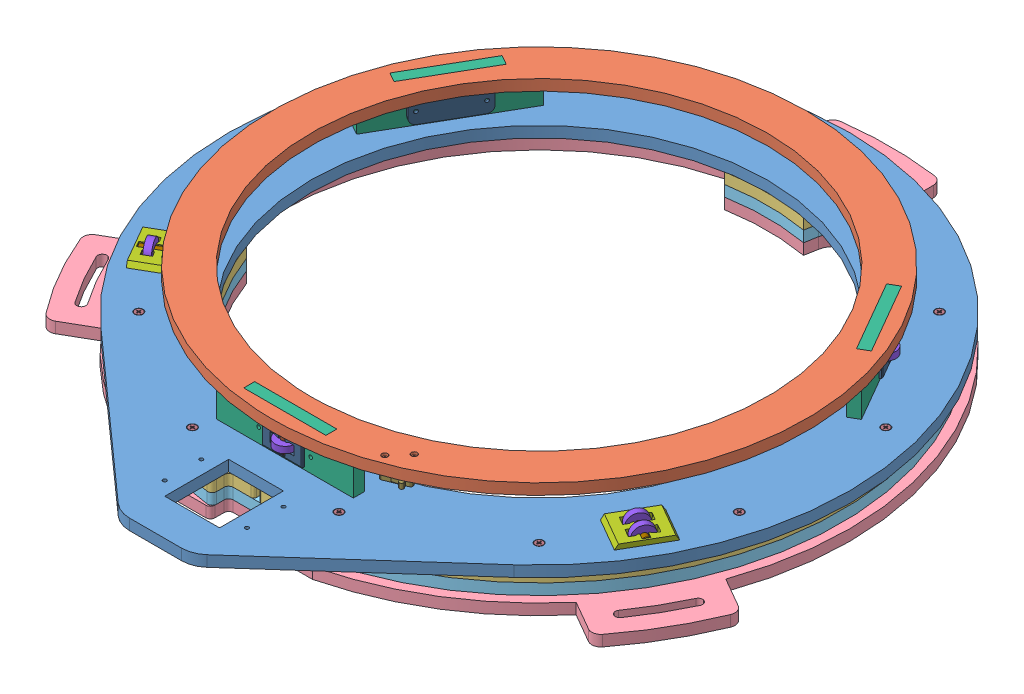
SolidWorks assembly Base Assembly - Plywood Parts, configuration Default. Lengths in mm.
Overall size (713.72 92.45 805).
48 component instances, 13 part files, 40 mates.
Components (placement in the parent):
- Base - Bottom Ring-1: Base - Bottom Ring [Default] at origin size (680 12 760)
- Base - Top Ring-1: Base - Top Ring [Default] at (0 114.9148 0) size (585 12 585)
- Base - Cable carrier ring-1: Base - Cable carrier ring [Default] at (0 -447.8958 0) x (1 0 0) z (0 -1 0) size (660 658.11 12)
- Base - Base Ring-1: Base - Base Ring [Default] at (0 34.4648 0) size (713.72 12 715)
- Base - Cable carrier ring lower-3: Base - Cable carrier ring lower [Default] at (0 58.4648 0) x (1 0 0) z (0 -1 0) size (660 658.11 12)
- Base - Uprights-4: Base - Uprights [Default] at (7.2575 0 46.252) size (150 56.45 12)
- Wide Roller Assem-4: Wide Roller Assem [Default] at (-232.883 45.169 131.3254) x (0.5 0 0.866025) z (-0.866025 0 0.5) size (52.45 32.7 42)
  - Wide Roller-1: Wide Roller [Default] at (2.4854 34.9145 44.1547) size (52.45 25.2 42)
  - 608 Bearing-1: 608 Bearing [Default] at (2.4854 38.9958 40.6547) x (1 0 0) z (0 -1 0) size (22 7 22)
  - 608 Bearing-2: 608 Bearing [Default] at (2.4854 38.9958 23.6547) x (1 0 0) z (0 -1 0) size (22 7 22)
  - Long 8mm Shaft-1: Long 8mm Shaft [Default] at (2.4854 38.9958 16.6547) size (8 8 38)
- Roller Assem-4: Roller Assem [Default] at (-3.9974 147.3095 228.5536) x (1 0 0) z (0 -1 0) size (70 29.66 25)
  - Roller-1: Roller [Default] at (3.7724 45.3652 49.3947) size (70 18.5 25)
  - 608 Bearing-1: 608 Bearing [Default] at (3.7724 49.4464 52.8947) x (0.903242 0.429132 0) z (-0.429132 0.903242 0) size (22 7 22)
  - Short 8mm Shaft-1: Short 8mm Shaft [Default] at (3.7724 49.4464 38.8947) size (8 8 21)
- Base - Uprights-5: Base - Uprights [Default] at (36.4267 0 -29.4112) x (-0.5 0 -0.866025) z (0.866025 0 -0.5) size (150 56.45 12)
- Base - Uprights-6: Base - Uprights [Default] at (-43.6841 0 -16.8408) x (-0.5 0 0.866025) z (-0.866025 0 -0.5) size (150 56.45 12)
- Roller Assem-5: Roller Assem [Default] at (199.9319 147.3095 -110.8149) x (-0.5 0 -0.866025) z (0 -1 0) size (70 29.66 25)
  - Roller-1: Roller [Default] at (3.7724 45.3652 49.3947) size (70 18.5 25)
  - 608 Bearing-1: 608 Bearing [Default] at (3.7724 49.4464 52.8947) x (0.903242 0.429132 0) z (-0.429132 0.903242 0) size (22 7 22)
  - Short 8mm Shaft-1: Short 8mm Shaft [Default] at (3.7724 49.4464 38.8947) size (8 8 21)
- Roller Assem-6: Roller Assem [Default] at (-195.9345 147.3095 -117.7386) x (-0.5 0 0.866025) z (0 -1 0) size (70 29.66 25)
  - Roller-1: Roller [Default] at (3.7724 45.3652 49.3947) size (70 18.5 25)
  - 608 Bearing-1: 608 Bearing [Default] at (3.7724 49.4464 52.8947) x (0.903242 0.429132 0) z (-0.429132 0.903242 0) size (22 7 22)
  - Short 8mm Shaft-1: Short 8mm Shaft [Default] at (3.7724 49.4464 38.8947) size (8 8 21)
- Wide Roller Assem-5: Wide Roller Assem [Default] at (230.1726 45.169 136.0199) x (0.5 0 -0.866025) z (0.866025 0 0.5) size (52.45 32.7 42)
  - Wide Roller-1: Wide Roller [Default] at (2.4854 34.9145 44.1547) size (52.45 25.2 42)
  - 608 Bearing-1: 608 Bearing [Default] at (2.4854 38.9958 40.6547) x (1 0 0) z (0 -1 0) size (22 7 22)
  - 608 Bearing-2: 608 Bearing [Default] at (2.4854 38.9958 23.6547) x (1 0 0) z (0 -1 0) size (22 7 22)
  - Long 8mm Shaft-1: Long 8mm Shaft [Default] at (2.4854 38.9958 16.6547) size (8 8 38)
- Wide Roller Assem-6: Wide Roller Assem [Default] at (2.7104 45.169 -267.3453) x (-1 0 0) z (0 0 -1) size (52.45 32.7 42)
  - Wide Roller-1: Wide Roller [Default] at (2.4854 34.9145 44.1547) size (52.45 25.2 42)
  - 608 Bearing-1: 608 Bearing [Default] at (2.4854 38.9958 40.6547) x (1 0 0) z (0 -1 0) size (22 7 22)
  - 608 Bearing-2: 608 Bearing [Default] at (2.4854 38.9958 23.6547) x (1 0 0) z (0 -1 0) size (22 7 22)
  - Long 8mm Shaft-1: Long 8mm Shaft [Default] at (2.4854 38.9958 16.6547) size (8 8 38)
- Limit Switch-1: Limit Switch [Default] at (113.6125 109.9148 243.8282) x (-0.927184 0 0.374607) z (0 1 0) size (37 27.92 10)
- flat head screw_am-14: flat head screw_am [B18.6.7M - M4 x 0.7 x 40 Type I Cross Recessed FHMS --40N] at (80.2339 82.4648 -299.437) x (0 -1 0) z (0 0 1) size (40 8.4 8.4)
- flat head screw_am-15: flat head screw_am [B18.6.7M - M4 x 0.7 x 40 Type I Cross Recessed FHMS --40N] at (219.2031 82.4648 -219.2031) x (0 -1 0) z (0 0 1) size (40 8.4 8.4)
- flat head screw_am-16: flat head screw_am [B18.6.7M - M4 x 0.7 x 40 Type I Cross Recessed FHMS --40N] at (299.437 82.4648 -80.2339) x (0 -1 0) z (0 0 1) size (40 8.4 8.4)
- flat head screw_am-17: flat head screw_am [B18.6.7M - M4 x 0.7 x 40 Type I Cross Recessed FHMS --40N] at (299.437 82.4648 80.2339) x (0 -1 0) z (0 0 1) size (40 8.4 8.4)
- flat head screw_am-18: flat head screw_am [B18.6.7M - M4 x 0.7 x 40 Type I Cross Recessed FHMS --40N] at (219.2031 82.4648 219.2031) x (0 -1 0) z (0 0 1) size (40 8.4 8.4)
- flat head screw_am-19: flat head screw_am [B18.6.7M - M4 x 0.7 x 40 Type I Cross Recessed FHMS --40N] at (80.2339 82.4648 299.437) x (0 -1 0) z (0 0 1) size (40 8.4 8.4)
- flat head screw_am-20: flat head screw_am [B18.6.7M - M4 x 0.7 x 40 Type I Cross Recessed FHMS --40N] at (-80.2339 82.4648 299.437) x (0 -1 0) z (0 0 1) size (40 8.4 8.4)
- flat head screw_am-21: flat head screw_am [B18.6.7M - M4 x 0.7 x 40 Type I Cross Recessed FHMS --40N] at (-219.2031 82.4648 219.2031) x (0 -1 0) z (0 0 1) size (40 8.4 8.4)
- flat head screw_am-22: flat head screw_am [B18.6.7M - M4 x 0.7 x 40 Type I Cross Recessed FHMS --40N] at (-299.437 82.4648 80.2339) x (0 -1 0) z (0 0 1) size (40 8.4 8.4)
- flat head screw_am-23: flat head screw_am [B18.6.7M - M4 x 0.7 x 40 Type I Cross Recessed FHMS --40N] at (-299.437 82.4648 -80.2339) x (0 -1 0) z (0 0 1) size (40 8.4 8.4)
- flat head screw_am-24: flat head screw_am [B18.6.7M - M4 x 0.7 x 40 Type I Cross Recessed FHMS --40N] at (-219.2031 82.4648 -219.2031) x (0 -1 0) z (0 0 1) size (40 8.4 8.4)
- flat head screw_am-25: flat head screw_am [B18.6.7M - M4 x 0.7 x 40 Type I Cross Recessed FHMS --40N] at (-80.2339 82.4648 -299.437) x (0 -1 0) z (0 0 1) size (40 8.4 8.4)
Mates (geometry in assembly coordinates):
- Concentric2: concentric anti-aligned: circle of Base - Bottom Ring-1; circle of Base - Cable carrier ring lower-3
- Coincident58: coincident anti-aligned: plane of Base - Cable carrier ring-1 through (0 58.4648 0) normal (0 -1 0); plane of Base - Cable carrier ring lower-3 through (0 58.4648 0) normal (0 1 0)
- Coincident59: coincident aligned: line of Base - Cable carrier ring-1 through (234.9232 70.4648 85.505) axis (0 -1 0); line of Base - Cable carrier ring lower-3 through (234.9232 58.4648 85.505) axis (0 -1 0)
- Coincident60: coincident anti-aligned: plane of Base - Base Ring-1 through (0 46.4648 0) normal (0 1 0); plane of Base - Cable carrier ring lower-3 through (0 46.4648 0) normal (0 -1 0)
- Coincident62: coincident anti-aligned: line of Base - Base Ring-1 through (43.412 34.4648 -246.2019) axis (0 1 0); line of Base - Cable carrier ring lower-3 through (43.412 58.4648 -246.2019) axis (0 -1 0)
- Concentric4: concentric aligned: cylinder of Base - Cable carrier ring-1 through (0 58.4648 0) axis (0 1 0) radius 330; cylinder of Base - Cable carrier ring lower-3 through (0 46.4648 0) axis (0 1 0) radius 330
- Coincident63: coincident anti-aligned: plane of Base - Cable carrier ring-1 through (0 58.4648 0) normal (0 -1 0); plane of Base - Cable carrier ring lower-3 through (0 58.4648 0) normal (0 1 0)
- Coincident64: coincident anti-aligned: plane of Base - Cable carrier ring-1 through (0 58.4648 0) normal (0 -1 0); plane of Base - Cable carrier ring lower-3 through (0 58.4648 0) normal (0 1 0)
- Coincident65: coincident anti-aligned: plane of Base - Bottom Ring-1 through (0 70.4648 0) normal (0 -1 0); plane of Base - Cable carrier ring-1 through (0 70.4648 0) normal (0 1 0)
- Concentric5: concentric aligned: circle of Base - Bottom Ring-1; circle of Base - Top Ring-1
- Concentric6: concentric anti-aligned: cylinder of Base - Bottom Ring-1 through (0 70.4648 0) axis (0 1 0) radius 340; cylinder of Base - Base Ring-1 through (0 46.4648 0) axis (0 -1 0) radius 340
- Parallel1: parallel aligned: plane of Base - Bottom Ring-1 through (-30 70.4648 310) normal (0 0 1); plane of Base - Base Ring-1 through (30 34.4648 310) normal (0 0 1)
- Coincident72: coincident anti-aligned: plane of Base - Bottom Ring-1 through (75 82.4648 278.5) normal (0 0 -1); plane of Base - Uprights-4 through (-75 114.9148 278.5) normal (0 0 1)
- Coincident73: coincident anti-aligned: plane of Base - Bottom Ring-1 through (75 82.4648 266.5) normal (-1 0 0); plane of Base - Uprights-4 through (75 114.9148 266.5) normal (1 0 0)
- Coincident74: coincident anti-aligned: plane of Base - Bottom Ring-1 through (0 82.4648 0) normal (0 1 0); plane of Base - Uprights-4 through (45 82.4648 266.5) normal (0 -1 0)
- Concentric7: concentric aligned: circle of Base - Bottom Ring-1; circle of Base - Top Ring-1
- Coincident76: coincident anti-aligned: plane of Base - Top Ring-1 through (0 114.9148 0) normal (0 -1 0); plane of Base - Uprights-4 through (45 114.9148 266.5) normal (0 1 0)
- Coincident82: coincident anti-aligned: plane of Base - Top Ring-1 through (45 114.9148 278.5) normal (-1 0 0); plane of Base - Uprights-4 through (45 126.9148 266.5) normal (1 0 0)
- Coincident84: coincident anti-aligned: plane of Base - Bottom Ring-1 through (-269.5922 70.4648 181.0526) normal (0.866025 0 -0.5); plane of Wide Roller Assem-4/Wide Roller-1 through (-280.7047 84.1648 161.8051) normal (-0.866025 0 0.5)
- Coincident85: coincident anti-aligned: plane of Base - Bottom Ring-1 through (-233.2192 70.4648 160.0526) normal (-0.5 0 -0.866025); plane of Wide Roller Assem-4/Wide Roller-1 through (-269.5922 82.4648 181.0526) normal (0.5 0 0.866025)
- Coincident86: coincident anti-aligned: plane of Base - Bottom Ring-1 through (0 82.4648 0) normal (0 1 0); plane of Wide Roller Assem-4/Wide Roller-1 through (-293.8172 82.4648 139.0936) normal (0 -1 0)
- Coincident87: coincident anti-aligned: plane of Base - Uprights-4 through (-22.225 85.4148 266.5) normal (0 1 0); plane of Roller Assem-4/Roller-1 through (-0.225 85.4148 278) normal (0 -1 0)
- Coincident88: coincident anti-aligned: plane of Base - Uprights-4 through (21.775 85.4148 266.5) normal (-1 0 0); plane of Roller Assem-4/Roller-1 through (21.775 85.4148 276.5) normal (1 0 0)
- Coincident89: coincident anti-aligned: plane of Base - Uprights-4 through (-75 114.9148 266.5) normal (0 0 -1); plane of Roller Assem-4/Roller-1 through (21.775 85.4148 266.5) normal (0 0 1)
- Coincident90: coincident anti-aligned: plane of Base - Top Ring-1 through (0 114.9148 0) normal (0 -1 0); plane of Limit Switch-1 through (90.2549 114.9148 255.4223) normal (0 1 0)
- Distance3: distance = 4 mm: point of Limit Switch-1; cylinder of Base - Top Ring-1 through (0 126.9148 0) axis (0 -1 0) radius 292.5
- Distance4: distance = 4 mm: point of Limit Switch-1; cylinder of Base - Top Ring-1 through (0 126.9148 0) axis (0 -1 0) radius 292.5
- Angle1: planar angle = 2.75762 rad aligned: plane of Limit Switch-1; plane of assembly through (0 0 0) normal (1 0 0)
- Coincident103: coincident aligned: cone of Base - Bottom Ring-1 through (80.2339 82.4648 -299.437) axis (0 -1 0); cone of flat head screw_am-14 through (80.2339 81.9648 -299.437) axis (0 -1 0)
- Coincident104: coincident aligned: cone of Base - Bottom Ring-1 through (219.2031 82.4648 -219.2031) axis (0 -1 0); cone of flat head screw_am-15 through (219.2031 81.9648 -219.2031) axis (0 -1 0)
- Coincident105: coincident aligned: cone of Base - Bottom Ring-1 through (299.437 82.4648 -80.2339) axis (0 -1 0); cone of flat head screw_am-16 through (299.437 81.9648 -80.2339) axis (0 -1 0)
- Coincident106: coincident aligned: cone of Base - Bottom Ring-1 through (299.437 82.4648 80.2339) axis (0 -1 0); cone of flat head screw_am-17 through (299.437 81.9648 80.2339) axis (0 -1 0)
- Coincident107: coincident aligned: cone of Base - Bottom Ring-1 through (219.2031 82.4648 219.2031) axis (0 -1 0); cone of flat head screw_am-18 through (219.2031 81.9648 219.2031) axis (0 -1 0)
- Coincident108: coincident aligned: cone of Base - Bottom Ring-1 through (80.2339 82.4648 299.437) axis (0 -1 0); cone of flat head screw_am-19 through (80.2339 81.9648 299.437) axis (0 -1 0)
- Coincident109: coincident aligned: cone of Base - Bottom Ring-1 through (-80.2339 82.4648 299.437) axis (0 -1 0); cone of flat head screw_am-20 through (-80.2339 81.9648 299.437) axis (0 -1 0)
- Coincident110: coincident aligned: cone of Base - Bottom Ring-1 through (-219.2031 82.4648 219.2031) axis (0 -1 0); cone of flat head screw_am-21 through (-219.2031 81.9648 219.2031) axis (0 -1 0)
- Coincident111: coincident aligned: cone of Base - Bottom Ring-1 through (-299.437 82.4648 80.2339) axis (0 -1 0); cone of flat head screw_am-22 through (-299.437 81.9648 80.2339) axis (0 -1 0)
- Coincident112: coincident aligned: cone of Base - Bottom Ring-1 through (-299.437 82.4648 -80.2339) axis (0 -1 0); cone of flat head screw_am-23 through (-299.437 81.9648 -80.2339) axis (0 -1 0)
- Coincident113: coincident aligned: cone of Base - Bottom Ring-1 through (-219.2031 82.4648 -219.2031) axis (0 -1 0); cone of flat head screw_am-24 through (-219.2031 81.9648 -219.2031) axis (0 -1 0)
- Coincident114: coincident aligned: cone of Base - Bottom Ring-1 through (-80.2339 82.4648 -299.437) axis (0 -1 0); cone of flat head screw_am-25 through (-80.2339 81.9648 -299.437) axis (0 -1 0)
